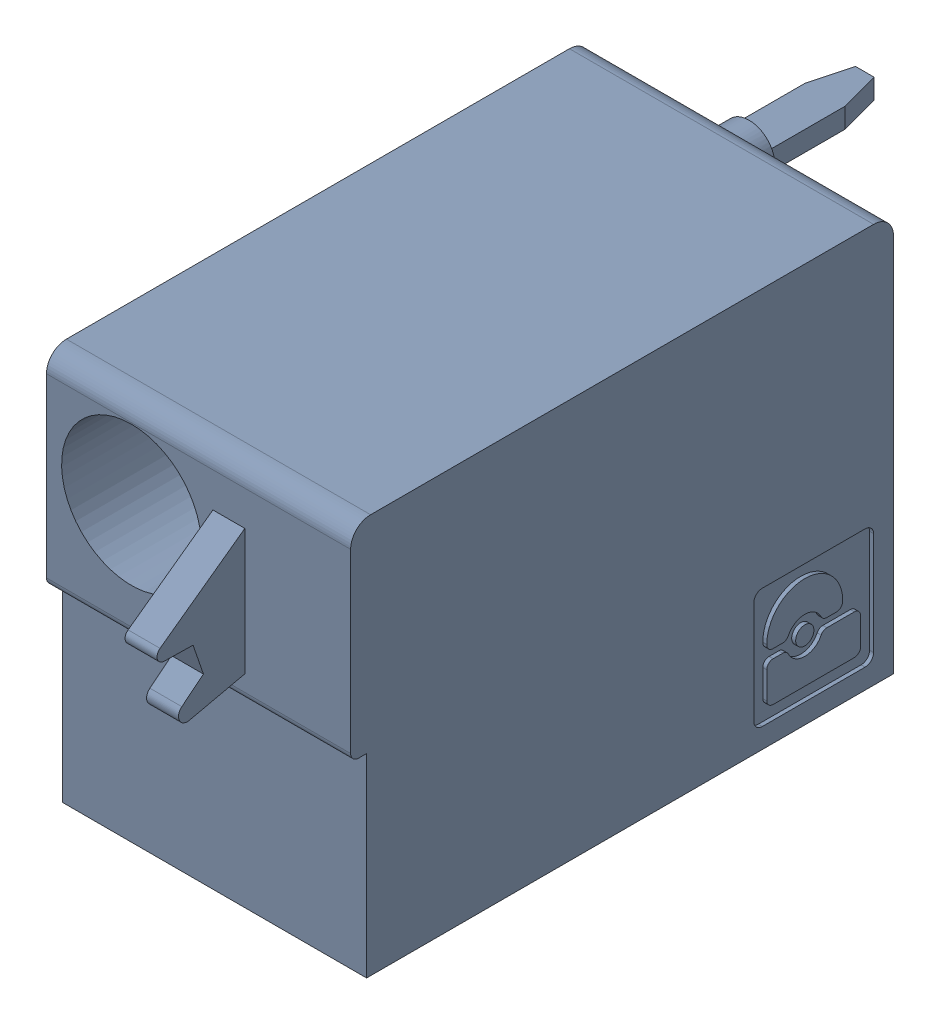
SolidWorks assembly J17, configuration Default. Lengths in mm.
Overall size (7.62 10 19.2).
2 component instances, 1 part files, 0 mates.
Components (placement in the parent):
- 1790487-1: 1790487 [Default] at (23.265 -15.67 -10.6) x (0 1 0) z (1 0 0) size (10 19.2 7.62)
  - ffkdsa1-v2-7.62-1: ffkdsa1-v2-7.62 [Default] at (-15.6914 -27.508 9.12) x (0 -1 0) z (0 0 1) size (19.2 10 7.62)
